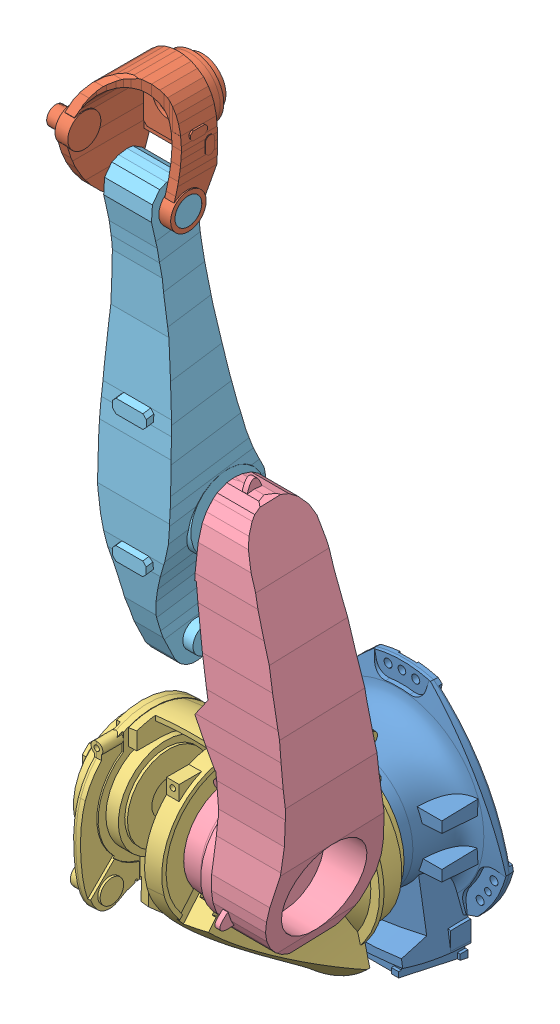
SolidWorks assembly AssemN01, configuration Default. Lengths in mm.
Overall size (807 2570.82 980.12).
5 component instances, 5 part files, 8 mates.
Components (placement in the parent):
- Part1-1: Part1 [Default] at origin size (629.29 670.6 298.5)
- Part10-1: Part10 [Default] at (2.2534 1910.1992 773.6873) x (0.00118 0.999999 0) z (-0.999999 0.00118 0) size (362.73 333.52 278)
- Part2-1: Part2 [Default] at (0.2595 219.9998 620) x (0.00118 0.999999 0) z (-0.999999 0.00118 0) size (813.53 742.49 651.71)
- Part3-1: Part3 [Default] at (1.2617 1069.5363 648.0493) x (0.001179 0.999455 0.032999) z (-0.999999 0.00118 0) size (1188.3 385.45 331.01)
- Part9-1: Part9 [Default] at (2.2534 1910.1992 773.6873) x (0.001167 0.989015 0.147809) z (-0.999999 0.00118 0) size (1331.58 323.8 230)
Mates (geometry in assembly coordinates):
- Concentric1: concentric aligned: circle of Part1-1; circle of Part2-1
- Coincident1: coincident anti-aligned: plane of Part1-1 through (0 0 200) normal (0 0 1); plane of Part2-1 through (0 0 200) normal (0 0 -1)
- Concentric2: concentric aligned: circle of Part2-1; circle of Part3-1
- Coincident2: coincident anti-aligned: plane of Part2-1 through (72.7595 219.9143 620) normal (0.999999 -0.00118 0); plane of Part3-1 through (72.7595 219.9143 620) normal (-0.999999 0.00118 0)
- Concentric3: concentric aligned: circle of Part3-1; circle of Part9-1
- Coincident4: coincident anti-aligned: plane of Part3-1 through (98.7616 1069.4213 648.0493) normal (-0.999999 0.00118 0); plane of Part9-1 through (98.7616 1069.4213 648.0493) normal (0.999999 -0.00118 0)
- Concentric4: concentric aligned: circle of Part10-1; circle of Part9-1
- Coincident5: coincident aligned: plane of Part10-1 through (117.2533 1910.0636 773.6873) normal (0.999999 -0.00118 0); plane of Part9-1 through (117.2533 1910.0636 773.6873) normal (0.999999 -0.00118 0)
